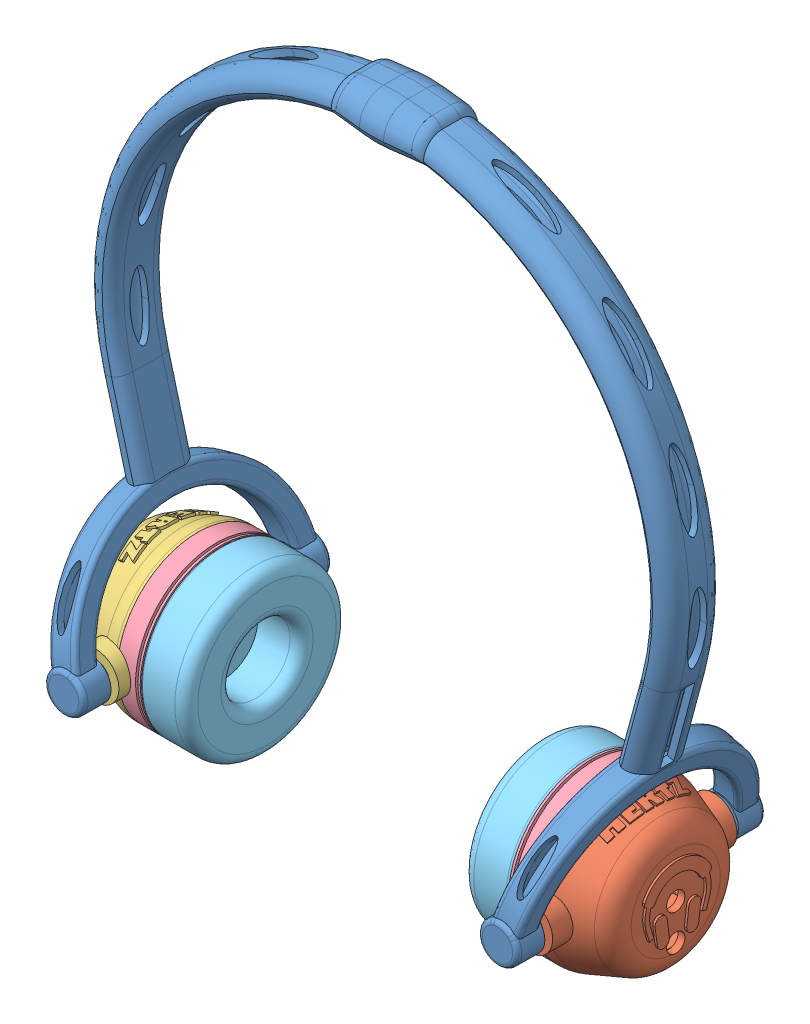
SolidWorks assembly headphone_assembly, configuration Default. Lengths in mm.
Overall size (254.98 282.86 108).
7 component instances, 5 part files, 16 mates.
Components (placement in the parent):
- headband-1: headband [Default] at (148.2432 -16.4585 141.671) size (254.98 257.28 108)
- earcup_r-1: earcup_r [Default] at (162.7523 15.288 204.442) x (0 0 -1) z (1 0 0) size (80 70.22 34.4)
- earcup_l-1: earcup_l [Default] at (2.9421 15.288 204.4296) x (0 0 1) z (-1 0 0) size (80 70.22 34.4)
- earcup_lid-1: earcup_lid [Default] at (162.7523 15.288 204.442) x (0 0 -1) z (1 0 0) size (70 70 12)
- earcup_lid-2: earcup_lid [Default] at (2.9421 15.288 204.4296) x (0 0 1) z (-1 0 0) size (70 70 12)
- earpad-1: earpad [Default] at (2.9421 15.288 204.4296) x (1 0 0) z (0 0 -1) size (20 70 70)
- earpad-2: earpad [Default] at (162.7523 15.288 204.442) x (-1 0 0) z (0 0 -1) size (20 70 70)
Mates (geometry in assembly coordinates):
- Coincident2: coincident aligned: circle of earcup_r-1; circle of earcup_lid-1
- Concentric1: concentric anti-aligned: circle of headband-1; circle of earcup_r-1
- Coincident3: coincident aligned: circle of earcup_r-1; circle of earcup_lid-1
- Concentric2: concentric anti-aligned: circle of headband-1; circle of earcup_l-1
- Coincident4: coincident aligned: circle of earcup_l-1; circle of earcup_lid-2
- Coincident5: coincident aligned: circle of earcup_l-1; circle of earcup_lid-2
- Distance2: distance = 2 mm anti-aligned: plane of earcup_l-1 through (-11.2694 14.2478 244.4296) normal (0 0 1); plane of headband-1 through (-11.2694 14.2478 246.4296) normal (0 0 -1)
- Distance3: distance = 2 mm anti-aligned: plane of earcup_r-1 through (176.9637 14.2478 244.4296) normal (0 0 1); plane of headband-1 through (176.9637 14.2478 246.4296) normal (0 0 -1)
- LimitAngle5: limit planar angle = 0.261799 rad aligned: plane of earcup_lid-1 through (162.7523 15.288 204.442) normal (-1 0 0); plane of headband-1 through (171.1516 15.7387 153.4303) normal (-0.965926 0.258819 0)
- LimitAngle6: limit planar angle = 0.261799 rad aligned: plane of earcup_lid-2 through (2.9421 15.288 204.4296) normal (1 0 0); plane of headband-1 through (-5.4572 15.7387 153.4303) normal (0.965926 0.258819 0)
- Concentric3: concentric aligned: circle of earcup_lid-2; circle of EarPad-1
- Concentric4: concentric aligned: circle of earcup_lid-1; circle of EarPad-2
- Coincident11: coincident anti-aligned: plane of earcup_lid-2; plane of EarPad-1
- Coincident12: coincident anti-aligned: plane of earcup_lid-1; plane of EarPad-2
- Coincident15: coincident anti-aligned: plane of earcup_lid-2 through (2.9421 15.288 204.4296) normal (0 1 0); plane of EarPad-1 through (2.9421 15.288 204.4296) normal (0 -1 0)
- Coincident16: coincident aligned: plane of earcup_lid-1 through (162.7523 15.288 204.442) normal (0 1 0); plane of EarPad-2 through (162.7523 15.288 204.442) normal (0 1 0)
